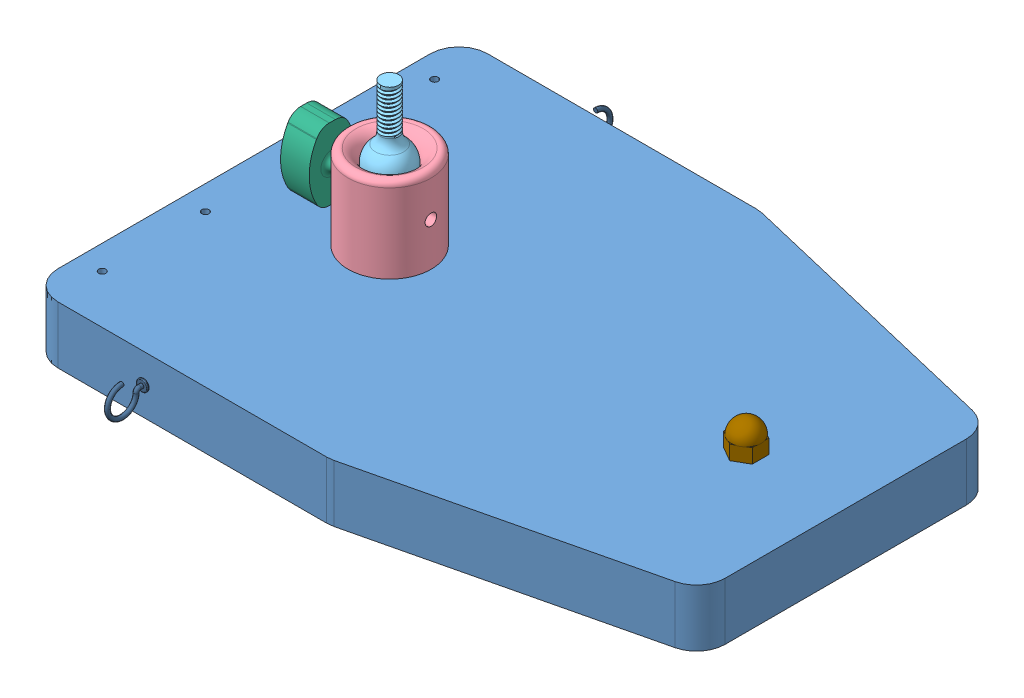
SolidWorks assembly BDT_S_A_17_v01, configuration Valor predeterminado. Lengths in mm.
Overall size (216 75 176.89).
17 component instances, 11 part files, 36 mates.
Components (placement in the parent):
- BDT_S_P_13_v01-1: BDT_S_P_13_v01 [Valor predeterminado] at origin size (210 20 150)
- BDT_S_P_15_v01-1: BDT_S_P_15_v01 [Valor predeterminado] at (16.5 -5 -15) x (1 0 0) z (0 0 -1) size (22.5 5 50)
- BDT_S_P_15_v01-2: BDT_S_P_15_v01 [Valor predeterminado] at (16.5 -5 65) x (1 0 0) z (0 0 -1) size (22.5 5 50)
- BDT_G_P_22_v01-2: BDT_G_P_22_v01 [Valor predeterminado] at (50.8 -6.2 0) x (1 0 0) z (0 0 -1) size (19.25 9.7 19.25)
- BDT_S_A_21_v01-1: BDT_S_A_21_v01 [Valor predeterminado] at (50.8 15 0) size (44.5 50 29)
  - BDT_S_P_18_v01-1: BDT_S_P_18_v01 [Valor predeterminado] at origin size (29 29.58 29)
  - BDT_S_P_19_v01-1: BDT_S_P_19_v01 [Valor predeterminado] at (0 25 0) x (0.004719 0 -0.999989) z (0.999989 0 0.004719) size (15 32.5 15)
  - BDT_S_P_20_v01-1: BDT_S_P_20_v01 [Valor predeterminado] at (-20 15 0) x (0 0 1) z (-1 0 0) size (16.13 25 20.11)
- BDT_G_F_25_v01-1: BDT_G_F_25_v01 [Valor predeterminado] at (175.26 -5 0) x (0 0 1) z (0 -1 0) size (11.55 10 5)
- flat countersunk head tapping screw_am-1: flat countersunk head tapping screw_am [FLATCKT 3.5x13x9.4-type I-AB-S] at (8.5 -6.7891 -58) x (0 1 0) z (-0.000006 0 -1) size (13 6.13 6.13)
- BDT_G_F_26_v01-1: BDT_G_F_26_v01 [Valor predeterminado] at (175.26 20 0) x (0 0 -1) z (0 -1 0) size (11.55 10.55 10.27)
- flat countersunk head tapping screw_am-2: flat countersunk head tapping screw_am [FLATCKT 3.5x13x9.4-type I-AB-S] at (8.5 -6.7891 -22) x (0 1 0) z (-0.000006 0 -1) size (13 6.13 6.13)
- flat countersunk head tapping screw_am-3: flat countersunk head tapping screw_am [FLATCKT 3.5x13x9.4-type I-AB-S] at (8.5 -6.7891 58) x (0 1 0) z (-0.000006 0 1) size (13 6.13 6.13)
- flat countersunk head tapping screw_am-4: flat countersunk head tapping screw_am [FLATCKT 3.5x13x9.4-type I-AB-S] at (8.5 -6.7891 22) x (0 1 0) z (-0.000006 0 1) size (13 6.13 6.13)
- BDT_G_F_24_v01-3: BDT_G_F_24_v01 [Valor predeterminado] at (40 5 -66.6942) x (0 -1 0) z (1 0 0) size (11.5 21.76 4)
- BDT_G_F_24_v01-4: BDT_G_F_24_v01 [Valor predeterminado] at (40 5 66.6942) x (0 -1 0) z (-1 0 0) size (11.5 21.76 4)
- TNUT-3-8-1: TNUT-3-8 [Default] at (50.8 5.3187 0) x (-1 0 0) z (0 0 1) size (26.78 12.72 26.78)
Mates (geometry in assembly coordinates):
- Coincidente1: coincident anti-aligned: plane of BDT_S_P_15_v01-1 through (16.5 -5 -65) normal (0 1 0); plane of BDT_S_P_13_v01-1 through (0 -5 0) normal (0 -1 0)
- Coincidente2: coincident aligned: plane of BDT_S_P_13_v01-1 through (0 -5 0) normal (-1 0 0); plane of BDT_S_P_15_v01-1 through (0 -10 -55) normal (-1 0 0)
- Coincidente3: coincident: line of BDT_S_P_13_v01-1 through (0 15 -65) axis (0 -1 0); plane of BDT_S_P_15_v01-1 through (-3.5 -7.5 -65) normal (0 0 -1)
- Concêntrico1: concentric aligned: cylinder of BDT_S_P_13_v01-1 through (50.8 -5 0) axis (0 -1 0) radius 3.5719; cylinder of BDT_G_P_22_v01-2 through (50.8 3 0) axis (0 -1 0) radius 4
- Coincidente4: coincident anti-aligned: plane of BDT_S_P_13_v01-1 through (0 -5 0) normal (0 -1 0); plane of BDT_G_P_22_v01-2 through (50.8 -5 0) normal (0 1 0)
- Paralelo1: parallel: plane of BDT_S_P_13_v01-1 through (0 -5 0) normal (-1 0 0); line of BDT_G_P_22_v01-2 through (50.8 -6.2 7.1) axis (0 0 1)
- Concêntrico2: concentric aligned: cylinder of BDT_S_P_13_v01-1 through (50.8 -5 0) axis (0 -1 0) radius 3.5719; cylinder of ? through (50.8 -9.5528 0) axis (0 -1 0) radius 5.5499
- Concêntrico3: concentric aligned: cylinder of ? through (50.8 -9.5528 0) axis (0 -1 0) radius 3.175; cylinder of BDT_S_A_21_v01-1/BDT_S_P_18_v01-1 through (50.8 25 0) axis (0 -1 0) radius 3.175
- Coincidente8: coincident anti-aligned: plane of BDT_S_P_13_v01-1 through (0 15 0) normal (0 1 0); plane of BDT_S_A_21_v01-1/BDT_S_P_18_v01-1 through (50.8 15 0) normal (0 -1 0)
- Coincidente9: coincident aligned: plane of BDT_G_P_22_v01-2 through (50.8 -6.2 0) normal (0 -1 0); circle of ?
- Concêntrico4: concentric aligned: cylinder of BDT_S_P_13_v01-1 through (175.26 15 0) axis (0 -1 0) radius 3.57; cylinder of ? through (175.26 8 0) axis (0 -1 0) radius 4
- Coincidente10: coincident anti-aligned: plane of BDT_S_P_13_v01-1 through (0 0 0) normal (0 -1 0); plane of ? through (175.26 0 0) normal (0 1 0)
- Concêntrico6: concentric aligned: cylinder of BDT_S_P_15_v01-2 through (7.5 -5 70) axis (0 1 0) radius 1.5; cone of ? through (7.5 -2.05 70) axis (0 1 0)
- Coincidente13: coincident anti-aligned: circle of BDT_S_P_15_v01-2; circle of ?
- Paralelo2: parallel aligned: plane of ? through (201.6942 5 35) normal (0 0 1); plane of assembly through (0 0 0) normal (0 0 1)
- Coincidente20: coincident anti-aligned: plane of BDT_S_P_13_v01-1 through (210 -5 0) normal (1 0 0); plane of ? through (210 5 35) normal (-1 0 0)
- Concêntrico14: concentric aligned: cylinder of BDT_S_P_13_v01-1 through (200 5 35) axis (1 0 0) radius 1; cylinder of ? through (201.6942 5 35) axis (1 0 0) radius 0.75
- Concêntrico17: concentric: cylinder of BDT_S_P_13_v01-1 through (7.5 15 30) axis (0 -1 0) radius 1.5; cylinder of ? through (7.5 -2.05 55) axis (0 1 0) radius 785.3982
- Coincidente21: coincident: circle of BDT_S_P_15_v01-2; circle of ?
- Coincidente22: coincident: circle of BDT_S_P_15_v01-2; circle of ?
- Concêntrico18: concentric anti-aligned: cylinder of BDT_S_P_13_v01-1 through (175.26 -5 0) axis (0 -1 0) radius 3.57; cylinder of BDT_G_F_25_v01-1 through (175.26 -10 0) axis (0 1 0) radius 3
- Coincidente26: coincident anti-aligned: plane of BDT_S_P_13_v01-1 through (0 15 0) normal (0 1 0); plane of ? through (175.26 15 0) normal (0 -1 0)
- Concêntrico19: concentric anti-aligned: cylinder of BDT_S_P_13_v01-1 through (175.26 15 0) axis (0 -1 0) radius 3.57; cylinder of ? through (175.26 15 0) axis (0 1 0) radius 3
- Paralelo3: parallel aligned: plane of BDT_S_P_13_v01-1 through (210 -5 0) normal (1 0 0); plane of BDT_G_F_25_v01-1 through (180.26 -10 -2.8868) normal (1 0 0)
- Coincidente11: coincident anti-aligned: plane of BDT_S_P_13_v01-1 through (0 15 0) normal (0 1 0); plane of BDT_G_F_26_v01-1 through (175.26 15 0) normal (0 -1 0)
- Concêntrico5: concentric anti-aligned: cylinder of BDT_S_P_13_v01-1 through (175.26 -5 0) axis (0 -1 0) radius 3.57; cylinder of BDT_G_F_26_v01-1 through (175.26 15 0) axis (0 1 0) radius 3
- Paralelo4: parallel aligned: plane of BDT_S_P_13_v01-1 through (210 -5 0) normal (1 0 0); plane of BDT_G_F_26_v01-1 through (180.26 15 -2.8868) normal (1 0 0)
- Coincidente28: coincident anti-aligned: plane of BDT_S_P_13_v01-1 through (0 -5 0) normal (0 -1 0); plane of BDT_G_F_25_v01-1 through (175.26 -5 0) normal (0 1 0)
- Concêntrico25: concentric aligned: cylinder of BDT_S_P_15_v01-1 through (8.5 -10 -58) axis (0 1 0) radius 2.5; cylinder of flat countersunk head tapping screw_am-1 through (8.5 -4.6842 -58) axis (0 1 0) radius 698.1317
- Coincidente30: coincident: circle of BDT_S_P_15_v01-1; cylinder of flat countersunk head tapping screw_am-1 through (8.5 -4.6842 -58) axis (0 1 0) radius 698.1317
- Concêntrico26: concentric aligned: cylinder of BDT_S_P_13_v01-1 through (40 5 75) axis (0 0 -1) radius 0.75; cylinder of BDT_G_F_24_v01-3 through (40 5 -66.6942) axis (0 0 -1) radius 0.75
- Coincidente31: coincident anti-aligned: plane of BDT_S_P_13_v01-1 through (0 -5 -75) normal (0 0 -1); plane of BDT_G_F_24_v01-3 through (40 5 -75) normal (0 0 1)
- Paralelo5: parallel anti-aligned: plane of BDT_G_F_24_v01-3 through (40 5 -66.6942) normal (0 -1 0); plane of assembly through (0 0 0) normal (0 1 0)
- Concêntrico27: concentric anti-aligned: cylinder of BDT_S_P_13_v01-1 through (50.8 -5 0) axis (0 1 0) radius 3.5719; cylinder of TNUT-3-8-1 through (50.8 5.3187 0) axis (0 -1 0) radius 5.5563
- Paralelo6: parallel aligned: plane of BDT_S_P_13_v01-1 through (0 -5 0) normal (-1 0 0); plane of TNUT-3-8-1 through (41.275 5.3187 -8.4003) normal (-1 0 0)
- Coincidente34: coincident anti-aligned: plane of BDT_S_P_13_v01-1 through (0 -5 0) normal (0 -1 0); plane of TNUT-3-8-1 through (50.8 -5 0) normal (0 1 0)
